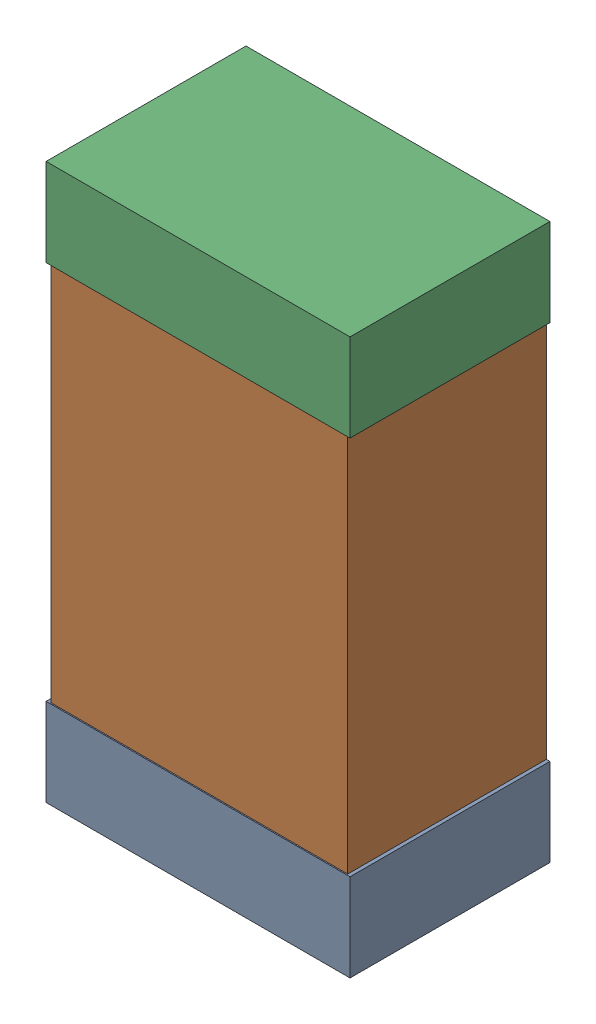
SolidWorks assembly C23Kanaloa_v2.0.0_Power, configuration Default. Lengths in mm.
Overall size (1.3 2.38 0.85).
6 component instances, 2 part files, 0 mates.
Components (placement in the parent):
- 330415056-1: 330415056 [Default] at (45.466 160.036 0) size (1.3 0.38 0.85)
  - Extruded_2-1: Extruded_2 [Default] at origin size (1.3 0.38 0.85)
- 352877008-1: 352877008 [Default] at (45.466 161.036 0) size (1.27 2.2 0.85)
  - Extruded_3-1: Extruded_3 [Default] at origin size (1.27 2.2 0.85)
- 330415056-2: 330415056 [Default] at (45.466 162.036 0) size (1.3 0.38 0.85)
  - Extruded_2-1: Extruded_2 [Default] at origin size (1.3 0.38 0.85)
